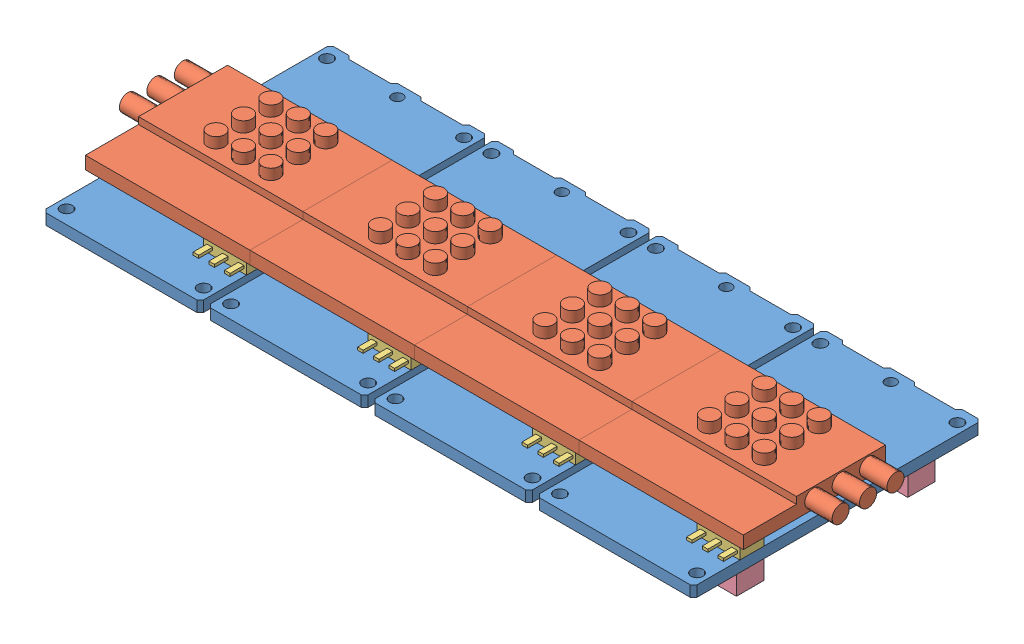
SolidWorks assembly IRS2_DC.revB2.4, configuration Default. Lengths in mm.
Overall size (104 10.55 42).
20 component instances, 4 part files, 0 mates.
Components (placement in the parent):
- IRS2_DC.revB2-1: IRS2_DC.revB2 [Default] at origin size (32 10.55 42)
  - IRS2_DC.revB2-1: IRS2_DC.revB2 [Default] at origin size (23 1.59 42)
  - IRS2_DC.revB2.heatsink-2: IRS2_DC.revB2.heatsink [Default] at origin size (32 7.55 20.75)
  - SOT-223-1: SOT-223 [Default] at (16.75 1.5875 -6.7541) size (6.25 1.55 7.25)
  - 80-pin-connectors-1: 80-pin-connectors [Default] x (-1 0 0) z (0 -1 0) size (22.38 29 3)
- IRS2_DC.revB2-2: IRS2_DC.revB2 [Default] at (24 0 0) size (32 10.55 42)
  - IRS2_DC.revB2-1: IRS2_DC.revB2 [Default] at origin size (23 1.59 42)
  - IRS2_DC.revB2.heatsink-2: IRS2_DC.revB2.heatsink [Default] at origin size (32 7.55 20.75)
  - SOT-223-1: SOT-223 [Default] at (16.75 1.5875 -6.7541) size (6.25 1.55 7.25)
  - 80-pin-connectors-1: 80-pin-connectors [Default] x (-1 0 0) z (0 -1 0) size (22.38 29 3)
- IRS2_DC.revB2-3: IRS2_DC.revB2 [Default] at (48 0 0) size (32 10.55 42)
  - IRS2_DC.revB2-1: IRS2_DC.revB2 [Default] at origin size (23 1.59 42)
  - IRS2_DC.revB2.heatsink-2: IRS2_DC.revB2.heatsink [Default] at origin size (32 7.55 20.75)
  - SOT-223-1: SOT-223 [Default] at (16.75 1.5875 -6.7541) size (6.25 1.55 7.25)
  - 80-pin-connectors-1: 80-pin-connectors [Default] x (-1 0 0) z (0 -1 0) size (22.38 29 3)
- IRS2_DC.revB2-4: IRS2_DC.revB2 [Default] at (72 0 0) size (32 10.55 42)
  - IRS2_DC.revB2-1: IRS2_DC.revB2 [Default] at origin size (23 1.59 42)
  - IRS2_DC.revB2.heatsink-2: IRS2_DC.revB2.heatsink [Default] at origin size (32 7.55 20.75)
  - SOT-223-1: SOT-223 [Default] at (16.75 1.5875 -6.7541) size (6.25 1.55 7.25)
  - 80-pin-connectors-1: 80-pin-connectors [Default] x (-1 0 0) z (0 -1 0) size (22.38 29 3)
